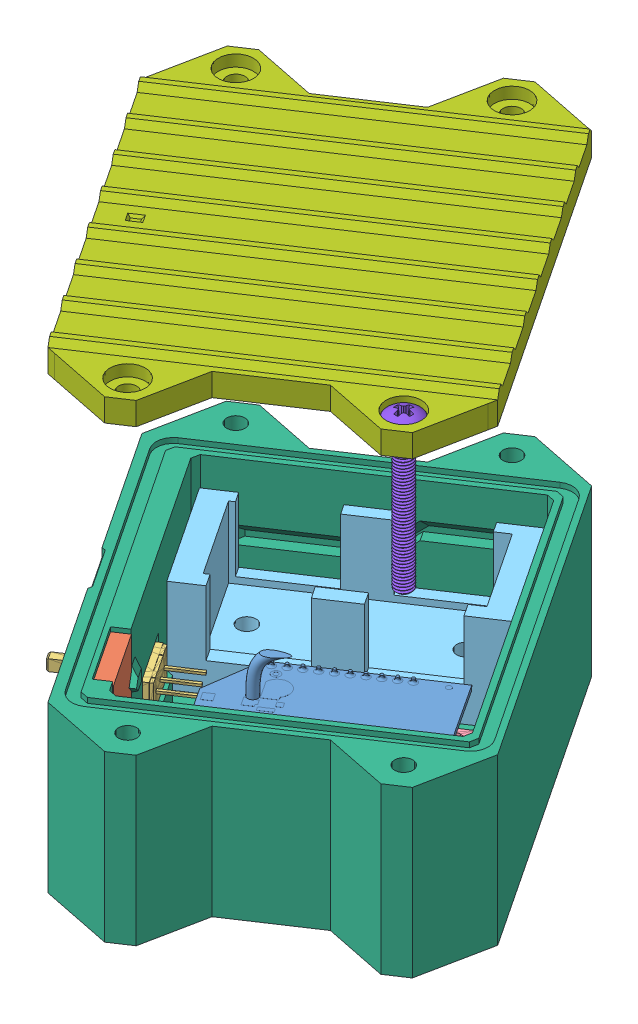
SolidWorks assembly Assem2, configuration Default. Lengths in mm.
Overall size (90.08 83.98 95.68).
9 component instances, 9 part files, 7 mates.
Components (placement in the parent):
- caja_xbee_base-1: caja_xbee_base [Default] at (11.8219 27.3989 31.464)
- XBeeProS1-1: XBeeProS1 [Default] at (-5.5242 50.9306 111.1327) x (0.833015 0 -0.55325) z (0.553133 0.020622 0.832838) size (32.94 15.19 23.73)
- VoltageRegulator U1V11F3-1: VoltageRegulator U1V11F3 [Default] at (-21.4218 58.1387 129.4492) x (-0.55325 0 -0.833015) z (0 -1 0) size (11.43 3 15.24)
- Selector Switch - SS12D00-1: Selector Switch - SS12D00 [Default] at (-26.3366 49.5985 107.0851) x (0.55325 0 0.833015) z (0 -1 0) size (8.79 19.84 4.97)
- XBee-Regulated.stl-1: XBee-Regulated.stl [Default] at (3.7813 42.4956 88.4689) x (-0.833015 0 0.55325) z (-0.011409 0.999787 -0.017178) size (34.29 27.94 6.63)
- CR123A_Holder-1: CR123A_Holder [Default] at (-18.0304 42.2193 86.3591) x (0.833015 0 -0.55325) z (0.55325 0 0.833015) size (43.9 20 20.5)
- Case base-1: Case base [Default] at (-4.0876 39.2596 115.0067) x (0.833015 0 -0.55325) z (0.55325 0 0.833015) size (57 29 77)
- Case Lid-1: Case Lid [Default] at (0.5543 115.2408 87.1196) x (0.833015 0 -0.55325) z (-0.55325 0 -0.833015) size (57 7 77)
- 92005A130_METRIC PAN HEAD PHILLIPS MACHINE SCREW-1: 92005A130_METRIC PAN HEAD PHILLIPS MACHINE SCREW [92005A130] at (22.6527 90.0408 120.0047) x (1 0 0) z (0 1 0) size (6 6 29.75)
Mates (geometry in assembly coordinates):
- Parallel1: parallel anti-aligned: plane of XBee-Regulated.stl-1 through (3.7813 42.4956 88.4689) normal (0.833015 0 -0.55325); plane of Case base-1 through (24.3344 41.2596 109.8843) normal (-0.833015 0 0.55325)
- Coincident21: coincident anti-aligned: plane of XBeeProS1-1 through (-5.4978 48.611 111.1726) normal (0.011409 -0.999787 0.017178); plane of XBee-Regulated.stl-1 through (3.7147 48.3244 88.3687) normal (-0.011409 0.999787 -0.017178)
- Parallel2: parallel anti-aligned: plane of XBeeProS1-1 through (11.0709 51.7137 99.7014) normal (0.833015 0 -0.55325); plane of Case base-1 through (24.3344 41.2596 109.8843) normal (-0.833015 0 0.55325)
- Coincident29: coincident anti-aligned: plane of Selector Switch - SS12D00-1 through (-25.2727 45.2596 106.2574) normal (0 -1 0); plane of Case base-1 through (-4.0876 45.2596 115.0067) normal (0 1 0)
- Coincident35: coincident aligned: plane of Selector Switch - SS12D00-1 through (-36.6709 50.229 113.8275) normal (-0.833015 0 0.55325); plane of Case base-1 through (-26.1542 39.2596 129.6623) normal (-0.833015 0 0.55325)
- Concentric2: concentric aligned: circle of Case base-1; line of 92005A130_METRIC PAN HEAD PHILLIPS MACHINE SCREW-1 through (22.6527 90.0408 120.0047) axis (0 1 0)
- Coincident47: coincident anti-aligned: plane of VoltageRegulator U1V11F3-1 through (-15.6618 47.2596 132.6994) normal (0 -1 0); plane of Case base-1 through (-18.122 47.2596 134.5262) normal (0 1 0)
